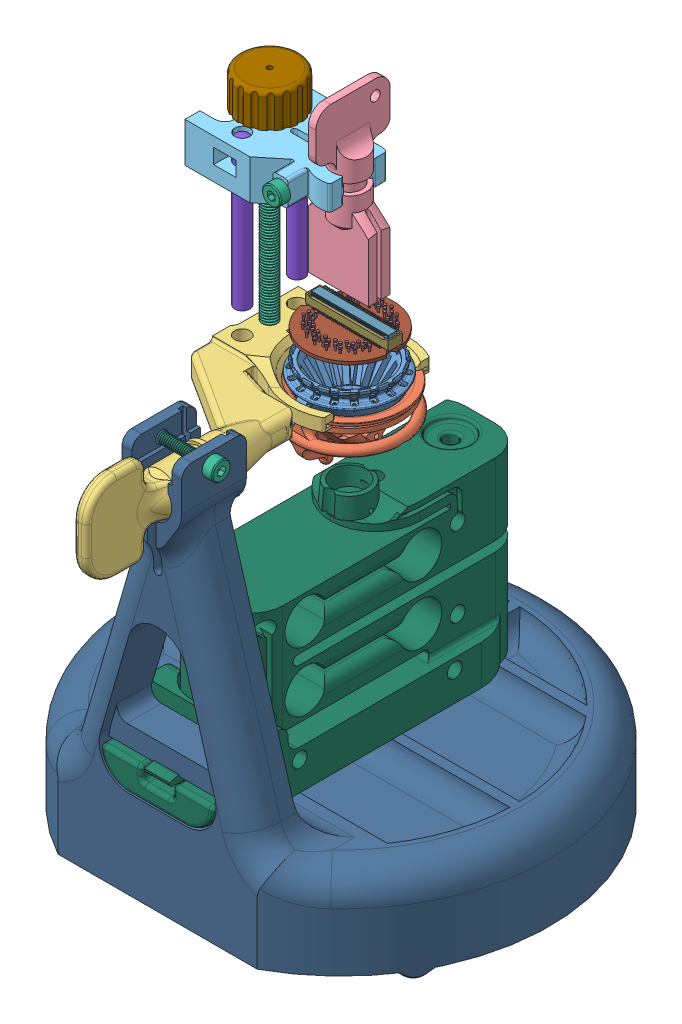
SolidWorks assembly mouse_jig_assembly, configuration Default. Lengths in mm.
Overall size (83.84 125.48 94.48).
82 component instances, 15 part files, 16 mates.
Components (placement in the parent):
- shuttle_drive_body-1: shuttle_drive_body [Default] at origin size (18.85 13.58 19.56)
- drive_holder_inner-1: drive_holder_inner [Default] at origin size (22.09 12.2 22)
- drive_holder_bottom-1: drive_holder_bottom [Default] at origin size (24.37 17.82 66.19)
- eib_holder_inner_two_omnetics-1: eib_holder_inner_two_omnetics [Default] at (0 13.9411 0) x (0 0 -1) z (1 0 0) size (15.35 33.98 12)
- eib_holder_top-1: eib_holder_top [Default] at (0 13.9944 0) size (25.85 8.5 18.2)
- socket head cap screw_am-2: socket head cap screw_am [B18.3.1M - 3 x 0.5 x 40 Hex SHCS -- 40SHX] at (-16 51.9944 0) x (0 -1 0) z (0 0 1) size (43 5.5 5.5)
- hex nut style 2_am-2: hex nut style 2_am [B18.2.4.2M - Hex nut, Style 2,  M3 x 0.5 --D-N] at (-16 38.0944 0) x (1 0 0) z (0 -1 0) size (5.5 6.35 2.9)
- dowel pin_a_jis-2: dowel pin_a_jis [JIS B 1355 Class A 3x30] at (-16 18.4608 -5.5) x (0 1 0) z (0.661955 0 0.749544) size (30 3 3)
- dowel pin_a_jis-3: dowel pin_a_jis [JIS B 1355 Class A 3x30] at (-16 18.5693 5.5) x (0 1 0) z (-0.978228 0 -0.207534) size (30 3 3)
- screw_thumbwheel-1: screw_thumbwheel [Default] at (-16 49.4943 0) x (0.023347 0 0.999727) z (-0.999727 0 0.023347) size (12.05 8 12.05)
- jig_base_big_rat-2: jig_base_big_rat [Default] at (0.0285 10.6426 1.6814) size (83.84 82.2 80.21)
- eib_64ch-1: eib_64ch [Default] at (0.1092 19.9251 -0.082) size (17.23 3.19 17.37)
  - eib_pcb_64ch-1: eib_pcb_64ch [Default] at origin size (17.23 0.6 17.37)
  - DF40C(2.0)-70DS_hirose_df40_receptacle-1: DF40C(2.0)-70DS_hirose_df40_receptacle [Default] at (3.1169 1.1424 -0.7469) x (0 0 -1) z (1 0 0) size (3.38 1.95 16.6)
  - neuralynx_gold_pin_small-1: neuralynx_gold_pin_small [Default] at (-5.664 1.718 3.6723) size (0.56 2.36 0.56)
  - neuralynx_gold_pin_small-2: neuralynx_gold_pin_small [Default] at (-4.9538 1.718 2.9684) size (0.56 2.36 0.56)
  - neuralynx_gold_pin_small-3: neuralynx_gold_pin_small [Default] at (-5.664 1.718 2.6723) size (0.56 2.36 0.56)
  - neuralynx_gold_pin_small-4: neuralynx_gold_pin_small [Default] at (-4.9538 1.718 1.9684) size (0.56 2.36 0.56)
  - neuralynx_gold_pin_small-5: neuralynx_gold_pin_small [Default] at (-4.252 1.718 5.2429) x (0.951057 0 -0.309017) z (0.309017 0 0.951057) size (0.56 2.36 0.56)
  - neuralynx_gold_pin_small-6: neuralynx_gold_pin_small [Default] at (-2.4238 1.718 6.3002) x (0.809017 0 -0.587785) z (0.587785 0 0.809017) size (0.56 2.36 0.56)
  - neuralynx_gold_pin_small-7: neuralynx_gold_pin_small [Default] at (-0.3583 1.718 6.7408) x (0.587785 0 -0.809017) z (0.809017 0 0.587785) size (0.56 2.36 0.56)
  - neuralynx_gold_pin_small-8: neuralynx_gold_pin_small [Default] at (1.7423 1.718 6.5216) x (0.309017 0 -0.951057) z (0.951057 0 0.309017) size (0.56 2.36 0.56)
  - neuralynx_gold_pin_small-9: neuralynx_gold_pin_small [Default] at (3.6723 1.718 5.664) x (0 0 -1) z (1 0 0) size (0.56 2.36 0.56)
  - neuralynx_gold_pin_small-10: neuralynx_gold_pin_small [Default] at (5.2429 1.718 4.252) x (-0.309017 0 -0.951057) z (0.951057 0 -0.309017) size (0.56 2.36 0.56)
  - neuralynx_gold_pin_small-11: neuralynx_gold_pin_small [Default] at (6.3002 1.718 2.4238) x (-0.587785 0 -0.809017) z (0.809017 0 -0.587785) size (0.56 2.36 0.56)
  - neuralynx_gold_pin_small-12: neuralynx_gold_pin_small [Default] at (-3.7941 1.718 4.3539) x (0.951057 0 -0.309017) z (0.309017 0 0.951057) size (0.56 2.36 0.56)
  - neuralynx_gold_pin_small-13: neuralynx_gold_pin_small [Default] at (-2.2629 1.718 5.3132) x (0.809017 0 -0.587785) z (0.587785 0 0.809017) size (0.56 2.36 0.56)
  - neuralynx_gold_pin_small-14: neuralynx_gold_pin_small [Default] at (-0.5103 1.718 5.7525) x (0.587785 0 -0.809017) z (0.809017 0 0.587785) size (0.56 2.36 0.56)
  - neuralynx_gold_pin_small-15: neuralynx_gold_pin_small [Default] at (1.2923 1.718 5.6286) x (0.309017 0 -0.951057) z (0.951057 0 0.309017) size (0.56 2.36 0.56)
  - neuralynx_gold_pin_small-16: neuralynx_gold_pin_small [Default] at (2.9684 1.718 4.9538) x (0 0 -1) z (1 0 0) size (0.56 2.36 0.56)
  - neuralynx_gold_pin_small-17: neuralynx_gold_pin_small [Default] at (4.3539 1.718 3.7941) x (-0.309017 0 -0.951057) z (0.951057 0 -0.309017) size (0.56 2.36 0.56)
  - neuralynx_gold_pin_small-18: neuralynx_gold_pin_small [Default] at (5.3132 1.718 2.2629) x (-0.587785 0 -0.809017) z (0.809017 0 -0.587785) size (0.56 2.36 0.56)
  - neuralynx_gold_pin_small-19: neuralynx_gold_pin_small [Default] at (-4.561 1.718 4.2918) x (0.951057 0 -0.309017) z (0.309017 0 0.951057) size (0.56 2.36 0.56)
  - neuralynx_gold_pin_small-20: neuralynx_gold_pin_small [Default] at (-3.0116 1.718 5.4912) x (0.809017 0 -0.587785) z (0.587785 0 0.809017) size (0.56 2.36 0.56)
  - neuralynx_gold_pin_small-21: neuralynx_gold_pin_small [Default] at (-1.1673 1.718 6.153) x (0.587785 0 -0.809017) z (0.809017 0 0.587785) size (0.56 2.36 0.56)
  - neuralynx_gold_pin_small-22: neuralynx_gold_pin_small [Default] at (0.7912 1.718 6.2126) x (0.309017 0 -0.951057) z (0.951057 0 0.309017) size (0.56 2.36 0.56)
  - neuralynx_gold_pin_small-23: neuralynx_gold_pin_small [Default] at (2.6723 1.718 5.664) x (0 0 -1) z (1 0 0) size (0.56 2.36 0.56)
  - neuralynx_gold_pin_small-24: neuralynx_gold_pin_small [Default] at (4.2918 1.718 4.561) x (-0.309017 0 -0.951057) z (0.951057 0 -0.309017) size (0.56 2.36 0.56)
  - neuralynx_gold_pin_small-25: neuralynx_gold_pin_small [Default] at (5.4912 1.718 3.0116) x (-0.587785 0 -0.809017) z (0.809017 0 -0.587785) size (0.56 2.36 0.56)
  - neuralynx_gold_pin_small-26: neuralynx_gold_pin_small [Default] at (-4.1031 1.718 3.4028) x (0.951057 0 -0.309017) z (0.309017 0 0.951057) size (0.56 2.36 0.56)
  - neuralynx_gold_pin_small-27: neuralynx_gold_pin_small [Default] at (-2.8507 1.718 4.5042) x (0.809017 0 -0.587785) z (0.587785 0 0.809017) size (0.56 2.36 0.56)
  - neuralynx_gold_pin_small-28: neuralynx_gold_pin_small [Default] at (-1.3193 1.718 5.1647) x (0.587785 0 -0.809017) z (0.809017 0 0.587785) size (0.56 2.36 0.56)
  - neuralynx_gold_pin_small-29: neuralynx_gold_pin_small [Default] at (0.3412 1.718 5.3196) x (0.309017 0 -0.951057) z (0.951057 0 0.309017) size (0.56 2.36 0.56)
  - neuralynx_gold_pin_small-30: neuralynx_gold_pin_small [Default] at (1.9684 1.718 4.9538) x (0 0 -1) z (1 0 0) size (0.56 2.36 0.56)
  - neuralynx_gold_pin_small-31: neuralynx_gold_pin_small [Default] at (3.4028 1.718 4.1031) x (-0.309017 0 -0.951057) z (0.951057 0 -0.309017) size (0.56 2.36 0.56)
  - neuralynx_gold_pin_small-32: neuralynx_gold_pin_small [Default] at (4.5042 1.718 2.8507) x (-0.587785 0 -0.809017) z (0.809017 0 -0.587785) size (0.56 2.36 0.56)
  - neuralynx_gold_pin_small-33: neuralynx_gold_pin_small [Default] at (-5.664 1.718 -3.6723) size (0.56 2.36 0.56)
  - neuralynx_gold_pin_small-34: neuralynx_gold_pin_small [Default] at (-4.9538 1.718 -2.9684) size (0.56 2.36 0.56)
  - neuralynx_gold_pin_small-35: neuralynx_gold_pin_small [Default] at (-5.664 1.718 -2.6723) size (0.56 2.36 0.56)
  - neuralynx_gold_pin_small-36: neuralynx_gold_pin_small [Default] at (-4.9538 1.718 -1.9684) size (0.56 2.36 0.56)
  - neuralynx_gold_pin_small-37: neuralynx_gold_pin_small [Default] at (-4.252 1.718 -5.2429) x (0.951057 0 0.309017) z (-0.309017 0 0.951057) size (0.56 2.36 0.56)
  - neuralynx_gold_pin_small-38: neuralynx_gold_pin_small [Default] at (-2.4238 1.718 -6.3002) x (0.809017 0 0.587785) z (-0.587785 0 0.809017) size (0.56 2.36 0.56)
  - neuralynx_gold_pin_small-39: neuralynx_gold_pin_small [Default] at (-0.3583 1.718 -6.7408) x (0.587785 0 0.809017) z (-0.809017 0 0.587785) size (0.56 2.36 0.56)
  - neuralynx_gold_pin_small-40: neuralynx_gold_pin_small [Default] at (1.7423 1.718 -6.5216) x (0.309017 0 0.951057) z (-0.951057 0 0.309017) size (0.56 2.36 0.56)
  - neuralynx_gold_pin_small-41: neuralynx_gold_pin_small [Default] at (3.6723 1.718 -5.664) x (0 0 1) z (-1 0 0) size (0.56 2.36 0.56)
  - neuralynx_gold_pin_small-42: neuralynx_gold_pin_small [Default] at (5.2429 1.718 -4.252) x (-0.309017 0 0.951057) z (-0.951057 0 -0.309017) size (0.56 2.36 0.56)
  - neuralynx_gold_pin_small-43: neuralynx_gold_pin_small [Default] at (6.3002 1.718 -2.4238) x (-0.587785 0 0.809017) z (-0.809017 0 -0.587785) size (0.56 2.36 0.56)
  - neuralynx_gold_pin_small-44: neuralynx_gold_pin_small [Default] at (-3.7941 1.718 -4.3539) x (0.951057 0 0.309017) z (-0.309017 0 0.951057) size (0.56 2.36 0.56)
  - neuralynx_gold_pin_small-45: neuralynx_gold_pin_small [Default] at (-2.2629 1.718 -5.3132) x (0.809017 0 0.587785) z (-0.587785 0 0.809017) size (0.56 2.36 0.56)
  - neuralynx_gold_pin_small-46: neuralynx_gold_pin_small [Default] at (-0.5103 1.718 -5.7525) x (0.587785 0 0.809017) z (-0.809017 0 0.587785) size (0.56 2.36 0.56)
  - neuralynx_gold_pin_small-47: neuralynx_gold_pin_small [Default] at (1.2923 1.718 -5.6286) x (0.309017 0 0.951057) z (-0.951057 0 0.309017) size (0.56 2.36 0.56)
  - neuralynx_gold_pin_small-48: neuralynx_gold_pin_small [Default] at (2.9684 1.718 -4.9538) x (0 0 1) z (-1 0 0) size (0.56 2.36 0.56)
  - neuralynx_gold_pin_small-49: neuralynx_gold_pin_small [Default] at (4.3539 1.718 -3.7941) x (-0.309017 0 0.951057) z (-0.951057 0 -0.309017) size (0.56 2.36 0.56)
  - neuralynx_gold_pin_small-50: neuralynx_gold_pin_small [Default] at (5.3132 1.718 -2.2629) x (-0.587785 0 0.809017) z (-0.809017 0 -0.587785) size (0.56 2.36 0.56)
  - neuralynx_gold_pin_small-51: neuralynx_gold_pin_small [Default] at (-4.561 1.718 -4.2918) x (0.951057 0 0.309017) z (-0.309017 0 0.951057) size (0.56 2.36 0.56)
  - neuralynx_gold_pin_small-52: neuralynx_gold_pin_small [Default] at (-3.0116 1.718 -5.4912) x (0.809017 0 0.587785) z (-0.587785 0 0.809017) size (0.56 2.36 0.56)
  - neuralynx_gold_pin_small-53: neuralynx_gold_pin_small [Default] at (-1.1673 1.718 -6.153) x (0.587785 0 0.809017) z (-0.809017 0 0.587785) size (0.56 2.36 0.56)
  - neuralynx_gold_pin_small-54: neuralynx_gold_pin_small [Default] at (0.7912 1.718 -6.2126) x (0.309017 0 0.951057) z (-0.951057 0 0.309017) size (0.56 2.36 0.56)
  - neuralynx_gold_pin_small-55: neuralynx_gold_pin_small [Default] at (2.6723 1.718 -5.664) x (0 0 1) z (-1 0 0) size (0.56 2.36 0.56)
  - neuralynx_gold_pin_small-56: neuralynx_gold_pin_small [Default] at (4.2918 1.718 -4.561) x (-0.309017 0 0.951057) z (-0.951057 0 -0.309017) size (0.56 2.36 0.56)
  - neuralynx_gold_pin_small-57: neuralynx_gold_pin_small [Default] at (5.4912 1.718 -3.0116) x (-0.587785 0 0.809017) z (-0.809017 0 -0.587785) size (0.56 2.36 0.56)
  - neuralynx_gold_pin_small-58: neuralynx_gold_pin_small [Default] at (-4.1031 1.718 -3.4028) x (0.951057 0 0.309017) z (-0.309017 0 0.951057) size (0.56 2.36 0.56)
  - neuralynx_gold_pin_small-59: neuralynx_gold_pin_small [Default] at (-2.8507 1.718 -4.5042) x (0.809017 0 0.587785) z (-0.587785 0 0.809017) size (0.56 2.36 0.56)
  - neuralynx_gold_pin_small-60: neuralynx_gold_pin_small [Default] at (-1.3193 1.718 -5.1647) x (0.587785 0 0.809017) z (-0.809017 0 0.587785) size (0.56 2.36 0.56)
  - neuralynx_gold_pin_small-61: neuralynx_gold_pin_small [Default] at (0.3412 1.718 -5.3196) x (0.309017 0 0.951057) z (-0.951057 0 0.309017) size (0.56 2.36 0.56)
  - neuralynx_gold_pin_small-62: neuralynx_gold_pin_small [Default] at (1.9684 1.718 -4.9538) x (0 0 1) z (-1 0 0) size (0.56 2.36 0.56)
  - neuralynx_gold_pin_small-63: neuralynx_gold_pin_small [Default] at (3.4028 1.718 -4.1031) x (-0.309017 0 0.951057) z (-0.951057 0 -0.309017) size (0.56 2.36 0.56)
  - neuralynx_gold_pin_small-64: neuralynx_gold_pin_small [Default] at (4.5042 1.718 -2.8507) x (-0.587785 0 0.809017) z (-0.809017 0 -0.587785) size (0.56 2.36 0.56)
- DF40C-70DP_hirose_df40_plug-1: DF40C-70DP_hirose_df40_plug [Default] at (-5.6361 22.2457 0.0263) x (0 0 1) z (1 0 0) size (2.97 1.14 15.52)
- socket head cap screw_am-4: socket head cap screw_am [B18.3.1M - 2 x 0.4 x 10 Hex SHCS -- 10SHX] at (8.0285 16.1426 33.6814) x (-1 0 0) z (0 0.924225 0.381849) size (12 3.8 3.8)
- socket head cap screw_am-5: socket head cap screw_am [B18.3.1M - 2 x 0.4 x 10 Hex SHCS -- 10SHX] at (-4.5 46.4944 11.2) x (0 0 -1) z (1 0 0) size (12 3.8 3.8)
- plating_jig_baseSLDPRT-1: plating_jig_baseSLDPRT [Default] at (-0.075 -41.1397 38.5906) x (0 0 -1) z (1 0 0) size (65 38.27 22.86)
Mates (geometry in assembly coordinates):
- Concentric1: concentric: cylinder of eib_holder_top-1 through (-16 40.9944 0) axis (0 1 0) radius 1.6; cylinder of socket head cap screw_am-2 through (-16 83.7444 0) axis (0 1 0) radius 2.75
- Coincident1: coincident: plane of eib_holder_top-1 through (-5.975 48.9944 0) normal (0 1 0); plane of socket head cap screw_am-2 through (-13.25 48.9944 0) normal (0 -1 0)
- Concentric2: concentric: cylinder of eib_holder_top-1 through (-16 40.9944 0) axis (0 1 0) radius 1.6; cylinder of hex nut style 2_am-2 through (-16 63.1319 0) axis (0 -1 0) radius 1.5
- Coincident2: coincident: plane of eib_holder_top-1 through (0 40.9944 0) normal (0 -1 0); plane of hex nut style 2_am-2 through (-16 40.9944 3.1754) normal (0 1 0)
- Concentric3: concentric: cylinder of drive_holder_bottom-1 through (-16 14.6363 -5.5) axis (0 -1 0) radius 1.55; cylinder of dowel pin_a_jis-2 through (-16 18.4608 -5.5) axis (0 -1 0) radius 1.5
- Concentric4: concentric: cylinder of drive_holder_bottom-1 through (-16 14.6363 5.5) axis (0 -1 0) radius 1.55; cylinder of dowel pin_a_jis-3 through (-16 18.5693 5.5) axis (0 -1 0) radius 1.5
- Concentric5: concentric: cylinder of socket head cap screw_am-2 through (-16 83.7444 0) axis (0 1 0) radius 2.75; cylinder of screw_thumbwheel-1 through (-16 52.3854 0) axis (0 -1 0) radius 2.765
- Concentric6: concentric: cylinder of jig_base_big_rat-2 through (6.0285 16.1426 33.6814) axis (-1 0 0) radius 1.2; cylinder of socket head cap screw_am-4 through (39.7785 16.1426 33.6814) axis (1 0 0) radius 1.9
- Coincident3: coincident: plane of jig_base_big_rat-2 through (6.0285 18.6426 26.6814) normal (1 0 0); plane of socket head cap screw_am-4 through (6.0285 15.417 35.4374) normal (-1 0 0)
- Concentric7: concentric: cylinder of eib_holder_top-1 through (-4.5 46.4944 -9) axis (0 0 1) radius 1; cylinder of socket head cap screw_am-5 through (-4.5 46.4944 42.95) axis (0 0 1) radius 1.9
- Coincident4: coincident: plane of eib_holder_top-1 through (0 13.9944 9.2) normal (0 0 1); plane of socket head cap screw_am-5 through (-4.5 48.3944 9.2) normal (0 0 -1)
- Coincident6: coincident: plane of jig_base_big_rat-2 through (0.0285 -44.3574 29.5213) normal (0 1 0); plane of plating_jig_baseSLDPRT-1 through (-0.075 -44.3574 -21.4094) normal (0 -1 0)
- Concentric8: concentric: cylinder of drive_holder_bottom-1 through (-16 14.6363 0) axis (0 -1 0) radius 1.45; cylinder of socket head cap screw_am-2 through (-16 83.7444 0) axis (0 1 0) radius 2.75
- Concentric9: concentric: cylinder of eib_holder_inner_two_omnetics-1 through (0 51.707 0) axis (0 1 0) radius 3.4177; cylinder of eib_holder_top-1 through (0 13.9944 0) axis (0 -1 0) radius 2.55
- Coincident7: coincident: plane of eib_holder_inner_two_omnetics-1 through (0 47.707 3.4489) normal (0 -1 0); plane of eib_holder_top-1 through (-3.3 47.707 0) normal (0 1 0)
- Concentric10: concentric: cylinder of eib_holder_top-1 through (-16 40.9944 5.5) axis (0 1 0) radius 1.5; cylinder of dowel pin_a_jis-3 through (-16 18.5693 5.5) axis (0 -1 0) radius 1.5
